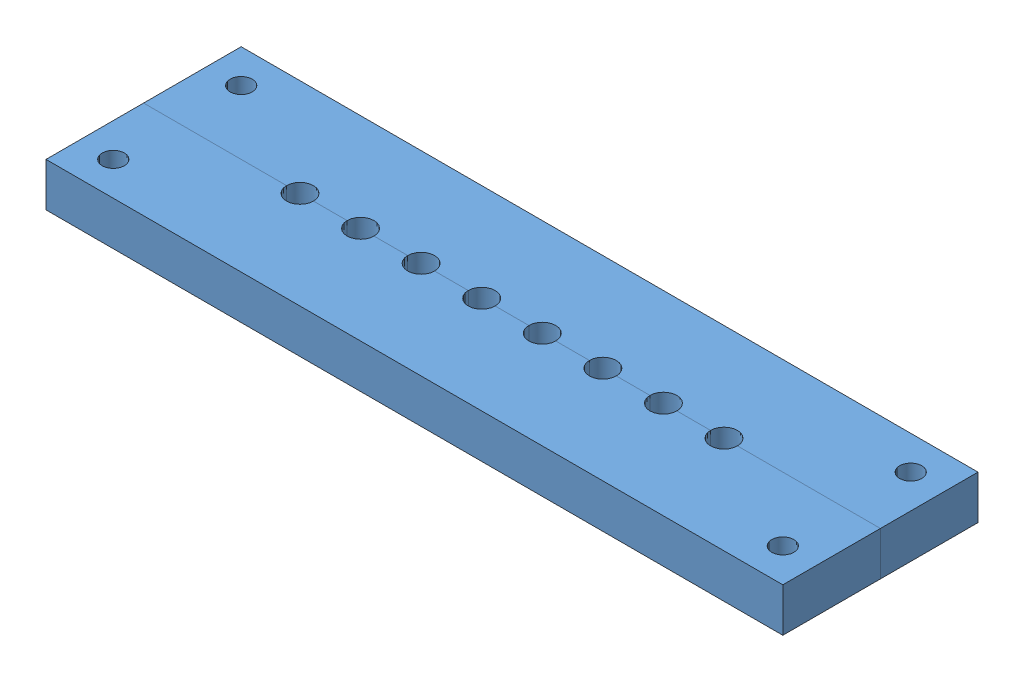
SolidWorks assembly LED_board and lower, configuration Default. Lengths in mm.
Overall size (109.48 8.5 29).
15 component instances, 4 part files, 3 mates.
Components (placement in the parent):
- Photodiode_lower_v3-1: Photodiode_lower_v3 [Default] at (55.3168 69.8197 80.6477) size (109.48 6.5 29)
- LED_Board_Capstone_T14-1: LED_Board_Capstone_T14 [Default] at (-24.8232 45.6447 40.7477) x (1 0 0) z (0 -1 0) size (109.48 29 0)
  - LED_Board_Capstone_T14_BOARD-1: LED_Board_Capstone_T14_BOARD [Default] at origin (suppressed, hidden)
  - FP-PEC06SBBN-MFG_CMP-25680-000045-1-1: FP-PEC06SBBN-MFG_CMP-25680-000045-1 [Default] at (114.26 53.13 0.4115) x (-1 0 0) z (0 0 1) (suppressed, hidden)
  - FP-PEC06SBBN-MFG_CMP-25680-000045-1-2: FP-PEC06SBBN-MFG_CMP-25680-000045-1 [Default] at (46.02 53.13 0.4115) x (-1 0 0) z (0 0 1) (suppressed, hidden)
  - FP-PEC06SBBN-MFG_CMP-25680-000045-1-3: FP-PEC06SBBN-MFG_CMP-25680-000045-1 [Default] at (114.26 26.67 0.4115) (suppressed, hidden)
  - FP-PEC06SBBN-MFG_CMP-25680-000045-1-4: FP-PEC06SBBN-MFG_CMP-25680-000045-1 [Default] at (46.02 26.67 0.4115) (suppressed, hidden)
  - LED_SST-10-SB-B130-M470_SST-10-SB-B130-M470-1-1: LED_SST-10-SB-B130-M470_SST-10-SB-B130-M470-1 [Default] at (111.64 39.953 0) x (0 -1 0) z (0 0 -1) (suppressed, hidden)
  - LED_SST-10-SB-B130-M470_SST-10-SB-B130-M470-1-2: LED_SST-10-SB-B130-M470_SST-10-SB-B130-M470-1 [Default] at (102.64 39.953 0) x (0 -1 0) z (0 0 -1) (suppressed, hidden)
  - LED_SST-10-SB-B130-M470_SST-10-SB-B130-M470-1-3: LED_SST-10-SB-B130-M470_SST-10-SB-B130-M470-1 [Default] at (93.64 39.953 0) x (0 -1 0) z (0 0 -1) (suppressed, hidden)
  - LED_SST-10-SB-B130-M470_SST-10-SB-B130-M470-1-4: LED_SST-10-SB-B130-M470_SST-10-SB-B130-M470-1 [Default] at (84.64 39.953 0) x (0 -1 0) z (0 0 -1) (suppressed, hidden)
  - LED_SST-10-SB-B130-M470_SST-10-SB-B130-M470-1-5: LED_SST-10-SB-B130-M470_SST-10-SB-B130-M470-1 [Default] at (75.64 39.953 0) x (0 -1 0) z (0 0 -1) (suppressed, hidden)
  - LED_SST-10-SB-B130-M470_SST-10-SB-B130-M470-1-6: LED_SST-10-SB-B130-M470_SST-10-SB-B130-M470-1 [Default] at (66.64 39.953 0) x (0 -1 0) z (0 0 -1) (suppressed, hidden)
  - LED_SST-10-SB-B130-M470_SST-10-SB-B130-M470-1-7: LED_SST-10-SB-B130-M470_SST-10-SB-B130-M470-1 [Default] at (57.64 39.953 0) x (0 -1 0) z (0 0 -1) (suppressed, hidden)
  - LED_SST-10-SB-B130-M470_SST-10-SB-B130-M470-1-8: LED_SST-10-SB-B130-M470_SST-10-SB-B130-M470-1 [Default] at (48.64 39.953 0) x (0 -1 0) z (0 0 -1) (suppressed, hidden)
Mates (geometry in assembly coordinates):
- Distance1: distance = 2 mm anti-aligned: plane of LED_Board_Capstone_T14-1/LED_Board_Capstone_T14_BOARD-1 through (-24.8232 45.6447 40.7477) normal (0 1 0); plane of Photodiode_lower_v3-1 through (55.3168 47.6447 95.1477) normal (0 -1 0)
- Coincident3: coincident aligned: plane of Photodiode_lower_v3-1 through (0.5768 69.8197 95.1477) normal (-1 0 0); plane of LED_Board_Capstone_T14-1/LED_Board_Capstone_T14_BOARD-1 through (0.5768 45.2332 80.6477) normal (-1 0 0)
- Coincident4: coincident aligned: plane of Photodiode_lower_v3-1 through (55.3168 69.8197 66.1477) normal (0 0 -1); plane of LED_Board_Capstone_T14-1/LED_Board_Capstone_T14_BOARD-1 through (110.0568 45.2332 66.1477) normal (0 0 -1)
